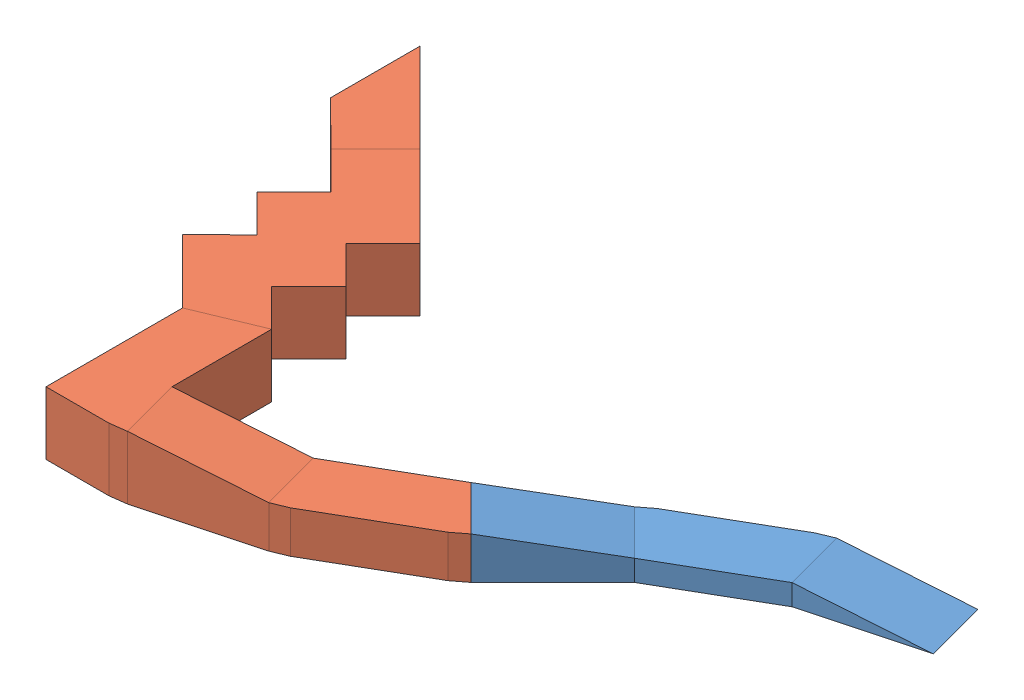
SolidWorks assembly Assem1, configuration Default. Lengths in mm.
Overall size (7639.44 600 4593.46).
2 component instances, 2 part files, 3 mates.
Components (placement in the parent):
- arena-1: arena [Default] at (5023.2097 2531.59 1005.0345) size (3217.23 400 2192.07)
- arena1-1: arena1 [Default] at (5801.0272 2531.59 227.217) size (7639.44 600 4593.46)
Mates (geometry in assembly coordinates):
- Coincident1: coincident: plane of arena-1 through (805.9818 1931.59 2193.2888) normal (-0.707107 0 0.707107); plane of arena1-1 through (1172.5039 2431.59 2559.8109) normal (0.707107 0 -0.707107)
- Coincident2: coincident: line of arena-1 through (805.9818 2331.59 2193.2888) axis (0.707107 0 0.707107); line of arena1-1 through (805.9818 2331.59 2193.2888) axis (0.707107 0 0.707107)
- Coincident3: coincident aligned: line of arena-1 through (805.9818 1931.59 2193.2888) axis (0 1 0); line of arena1-1 through (805.9818 1931.59 2193.2888) axis (0 1 0)
